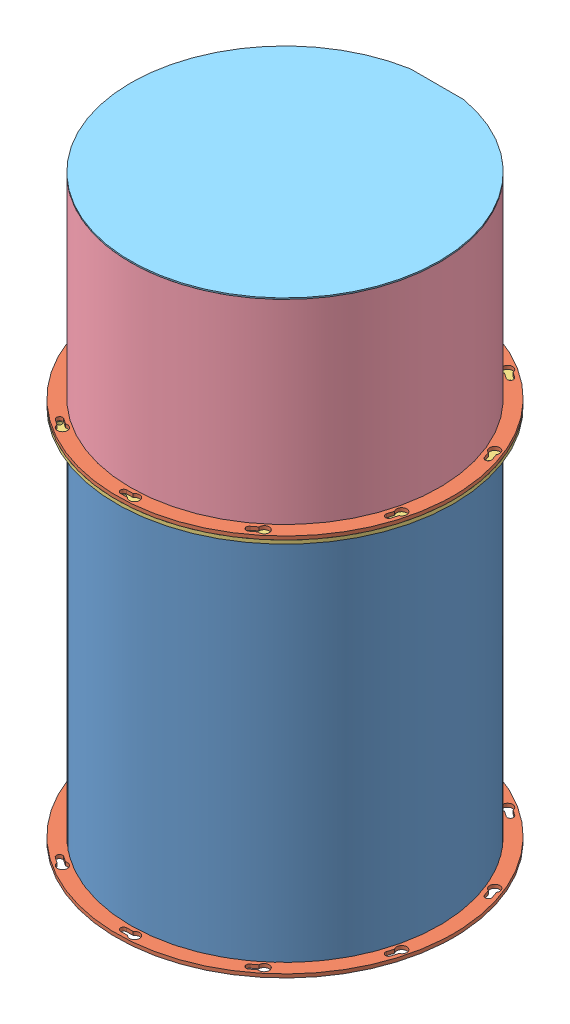
SolidWorks assembly Z-axis_Cover_Rolling_Assy, configuration Default. Lengths in mm.
Overall size (382 656.5 382).
6 component instances, 5 part files, 15 mates.
Components (placement in the parent):
- Z-axis_Cover_Rolling-1: Z-axis_Cover_Rolling [Default] at origin size (350 430 346.43)
- Z-axis_Cover_Rolling_Flange-1: Z-axis_Cover_Rolling_Flange [Default] x (1 0 0) z (0 1 0) size (382 382 4)
- Z-axis_Cover_Rolling_Flange_Threads-1: Z-axis_Cover_Rolling_Flange_Threads [Default] at (0 430 0) x (-1 0 0) z (0 -1 0) size (382 382 4)
- Z-axis_Cover_Rolling_Flange-4: Z-axis_Cover_Rolling_Flange [Default] at (0 430 0) x (1 0 0) z (0 1 0) size (382 382 4)
- Z-axis_Cover_Rolling_BottomSleeve-1: Z-axis_Cover_Rolling_BottomSleeve [Default] at (0 430 0) size (350 225 346.43)
- Z-Cover_BottomPlate-1: Z-Cover_BottomPlate [Default] at (0 655 0) size (350 1.5 347.39)
Mates (geometry in assembly coordinates):
- Coincident4: coincident aligned: plane of Z-axis_Cover_Rolling-1 through (0 0 0) normal (0 -1 0); plane of Z-axis_Cover_Rolling_Flange-1 through (0 0 0) normal (0 -1 0)
- Coincident6: coincident anti-aligned: plane of Z-axis_Cover_Rolling-1 through (0 0 0) normal (0 0 1); plane of Z-axis_Cover_Rolling_Flange-1 through (0 0 0) normal (0 0 -1)
- Coincident7: coincident aligned: plane of Z-axis_Cover_Rolling_Flange-1 through (0 0 0) normal (1 0 0)
- Coincident8: coincident aligned: plane of Z-axis_Cover_Rolling-1 through (0 430 0) normal (0 1 0); plane of Z-axis_Cover_Rolling_Flange_Threads-1 through (0 430 0) normal (0 1 0)
- Coincident9: coincident anti-aligned: plane of Z-axis_Cover_Rolling-1 through (0 0 0) normal (0 0 1); plane of Z-axis_Cover_Rolling_Flange_Threads-1 through (0 430 0) normal (0 0 -1)
- Coincident10: coincident anti-aligned: plane of Z-axis_Cover_Rolling-1 through (0 0 0) normal (1 0 0); plane of Z-axis_Cover_Rolling_Flange_Threads-1 through (0 430 0) normal (-1 0 0)
- Coincident11: coincident anti-aligned: plane of Z-axis_Cover_Rolling_Flange_Threads-1 through (0 430 0) normal (0 1 0); plane of Z-axis_Cover_Rolling_Flange-4 through (0 430 0) normal (0 -1 0)
- Coincident12: coincident anti-aligned: plane of Z-axis_Cover_Rolling-1 through (0 0 0) normal (0 0 1); plane of Z-axis_Cover_Rolling_Flange-4 through (0 430 0) normal (0 0 -1)
- Coincident13: coincident aligned: plane of Z-axis_Cover_Rolling-1 through (0 0 0) normal (1 0 0); plane of Z-axis_Cover_Rolling_Flange-4 through (0 430 0) normal (1 0 0)
- Coincident14: coincident anti-aligned: plane of Z-axis_Cover_Rolling-1 through (0 430 0) normal (0 1 0); plane of Z-axis_Cover_Rolling_BottomSleeve-1 through (0 430 0) normal (0 -1 0)
- Coincident15: coincident aligned: plane of Z-axis_Cover_Rolling-1 through (0 0 0) normal (0 0 1); plane of Z-axis_Cover_Rolling_BottomSleeve-1 through (0 430 0) normal (0 0 1)
- Coincident16: coincident aligned: plane of Z-axis_Cover_Rolling-1 through (0 0 0) normal (1 0 0); plane of Z-axis_Cover_Rolling_BottomSleeve-1 through (0 430 0) normal (1 0 0)
- Coincident20: coincident anti-aligned: plane of Z-axis_Cover_Rolling_BottomSleeve-1 through (0 655 0) normal (0 1 0); plane of Z-Cover_BottomPlate-1 through (0 655 0) normal (0 -1 0)
- Coincident21: coincident aligned: plane of Z-axis_Cover_Rolling-1 through (0 0 0) normal (0 0 1); plane of Z-Cover_BottomPlate-1 through (0 655 0) normal (0 0 1)
- Coincident22: coincident aligned: plane of Z-axis_Cover_Rolling-1 through (0 0 0) normal (1 0 0); plane of Z-Cover_BottomPlate-1 through (0 655 0) normal (1 0 0)
